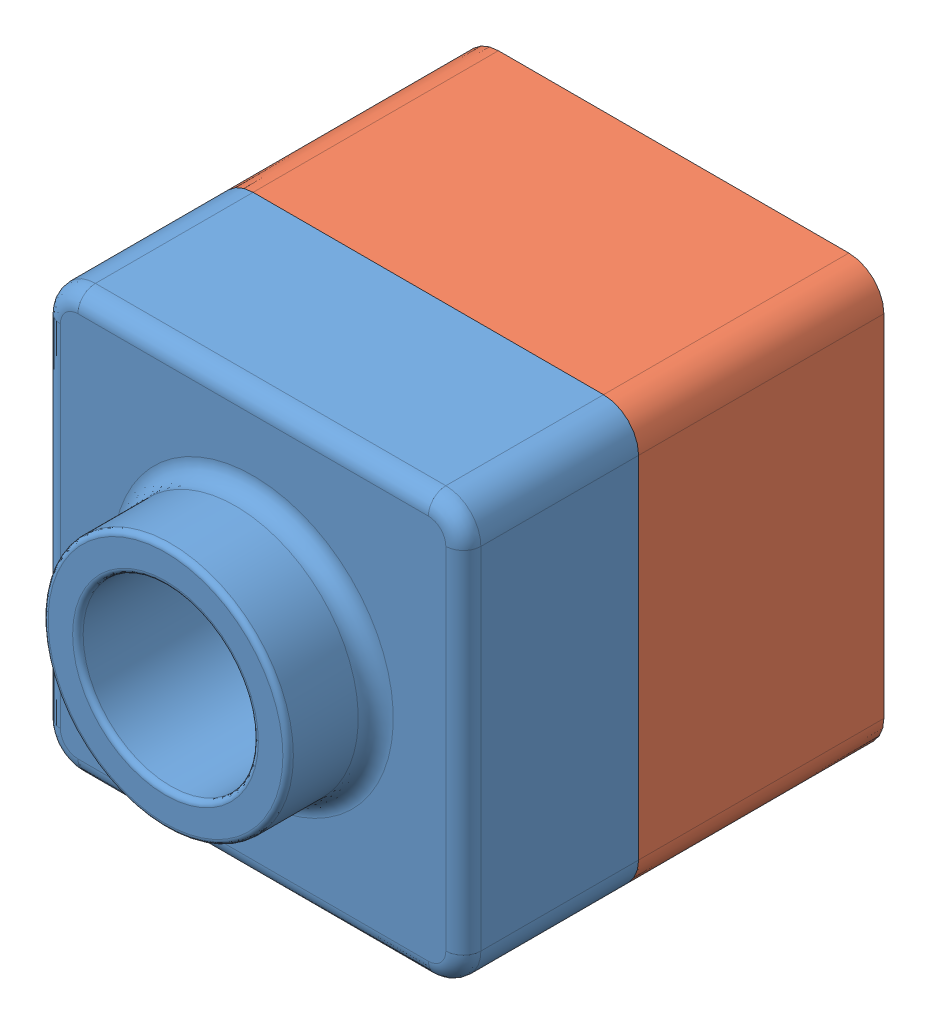
SolidWorks assembly tutor, configuration Default. Lengths in mm.
Overall size (120 120 145).
2 component instances, 2 part files, 4 mates.
Components (placement in the parent):
- tutor1-1: tutor1 [Default] at (1.0561 49.7916 123.9067) size (120 120 75)
- tutor2-1: tutor2 [Default] at (1.0561 49.7916 53.9067) size (120 120 90)
Mates (geometry in assembly coordinates):
- Coincident1: coincident: plane of tutor1-1 through (1.0561 49.7916 123.9067) normal (0 0 -1); plane of tutor2-1 through (-237.6087 159.7916 123.9067) normal (0 0 1)
- Coincident2: coincident: plane of tutor1-1 through (1.0561 49.7916 173.9067) normal (0 -1 0); plane of tutor2-1 through (-247.6087 49.7916 143.9067) normal (0 -1 0)
- Coincident5: coincident: plane of tutor1-1 through (1.0561 49.7916 123.9067) normal (0 0 -1); plane of tutor2-1 through (11.0561 159.7916 123.9067) normal (0 0 1)
- Coincident6: coincident aligned: plane of tutor1-1 through (121.0561 49.7916 173.9067) normal (1 0 0); plane of tutor2-1 through (121.0561 49.7916 143.9067) normal (1 0 0)
